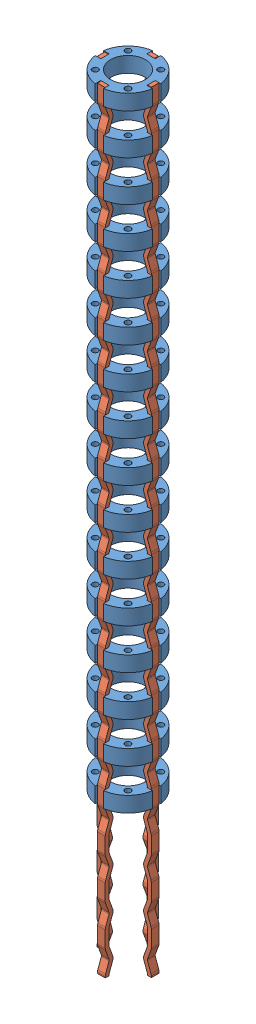
SolidWorks assembly Spine3Segments, configuration Default. Lengths in mm.
Overall size (14.85 168.25 14.85).
20 component instances, 2 part files, 9 mates.
Components (placement in the parent):
- RigidDisc-1: RigidDisc [Default] at (4.4669 6.9477 12.6403) size (14.85 4 14.85)
- RigidDisc-2: RigidDisc [Default] at (4.4669 -3.5523 12.6403) size (14.85 4 14.85)
- RigidDisc-3: RigidDisc [Default] at (4.4669 -14.0523 12.6403) size (14.85 4 14.85)
- RigidDisc-4: RigidDisc [Default] at (4.4669 -24.5523 12.6403) size (14.85 4 14.85)
- RigidDisc-5: RigidDisc [Default] at (4.4669 -35.0523 12.6403) size (14.85 4 14.85)
- Ligament-9: Ligament [Default] at (10.9419 10.9477 11.5653) x (0 -1 0) z (-1 0 0) size (168.25 2 2.03)
- RigidDisc-16: RigidDisc [Default] at (4.4669 -45.5523 12.6403) size (14.85 4 14.85)
- RigidDisc-17: RigidDisc [Default] at (4.4669 -56.0523 12.6403) size (14.85 4 14.85)
- RigidDisc-18: RigidDisc [Default] at (4.4669 -66.5523 12.6403) size (14.85 4 14.85)
- RigidDisc-19: RigidDisc [Default] at (4.4669 -77.0523 12.6403) size (14.85 4 14.85)
- RigidDisc-20: RigidDisc [Default] at (4.4669 -87.5523 12.6403) size (14.85 4 14.85)
- RigidDisc-21: RigidDisc [Default] at (4.4669 -98.0523 12.6403) size (14.85 4 14.85)
- RigidDisc-22: RigidDisc [Default] at (4.4669 -108.5523 12.6403) size (14.85 4 14.85)
- RigidDisc-23: RigidDisc [Default] at (4.4669 -119.0523 12.6403) size (14.85 4 14.85)
- RigidDisc-24: RigidDisc [Default] at (4.4669 -129.5523 12.6403) size (14.85 4 14.85)
- RigidDisc-25: RigidDisc [Default] at (4.4669 -140.0523 12.6403) size (14.85 4 14.85)
- RigidDisc-26: RigidDisc [Default] at (4.4669 -150.5523 12.6403) size (14.85 4 14.85)
- Ligament-11: Ligament [Default] at (3.3919 10.9477 6.1653) x (0 -1 0) z (0 0 1) size (168.25 2 2.03)
- Ligament-12: Ligament [Default] at (-2.0081 10.9477 13.7153) x (0 -1 0) z (1 0 0) size (168.25 2 2.03)
- Ligament-13: Ligament [Default] at (5.5419 10.9477 19.1153) x (0 -1 0) z (0 0 -1) size (168.25 2 2.03)
Mates (geometry in assembly coordinates):
- Coincident21: coincident anti-aligned: plane of RigidDisc-1 through (4.4669 6.9477 13.7153) normal (0 0 -1); plane of Ligament-5 through (-1.0081 -150.626 13.7153) normal (0 0 1)
- Coincident23: coincident anti-aligned: plane of RigidDisc-1 through (-1.5081 6.9477 11.5653) normal (-1 0 0); plane of Ligament-5 through (-1.5081 -188.4786 11.7153) normal (1 0 0)
- Coincident25: coincident anti-aligned: plane of RigidDisc-1 through (3.3919 6.9477 12.6403) normal (1 0 0); plane of Ligament-8 through (3.3919 -150.626 7.1653) normal (-1 0 0)
- Coincident26: coincident anti-aligned: plane of RigidDisc-1 through (5.5419 6.9477 6.6653) normal (0 0 -1); plane of Ligament-8 through (5.3919 -188.4786 6.6653) normal (0 0 1)
- Coincident29: coincident anti-aligned: plane of RigidDisc-1 through (10.4419 6.9477 13.7153) normal (1 0 0); plane of Ligament-9 through (10.4419 -30.9786 13.5653) normal (-1 0 0)
- Coincident30: coincident anti-aligned: plane of RigidDisc-1 through (4.4669 6.9477 11.5653) normal (0 0 1); plane of Ligament-9 through (9.9419 6.874 11.5653) normal (0 0 -1)
- Coincident32: coincident anti-aligned: plane of RigidDisc-1 through (3.3919 6.9477 18.6153) normal (0 0 1); plane of Ligament-10 through (3.5419 -188.4786 18.6153) normal (0 0 -1)
- Coincident33: coincident anti-aligned: plane of RigidDisc-1 through (5.5419 6.9477 12.6403) normal (-1 0 0); plane of Ligament-10 through (5.5419 -150.626 18.1153) normal (1 0 0)
- Coincident34: coincident aligned: plane of RigidDisc-1 through (4.4669 10.9477 12.6403) normal (0 1 0); plane of Ligament-9 through (11.4419 10.9477 13.5653) normal (0 1 0)
